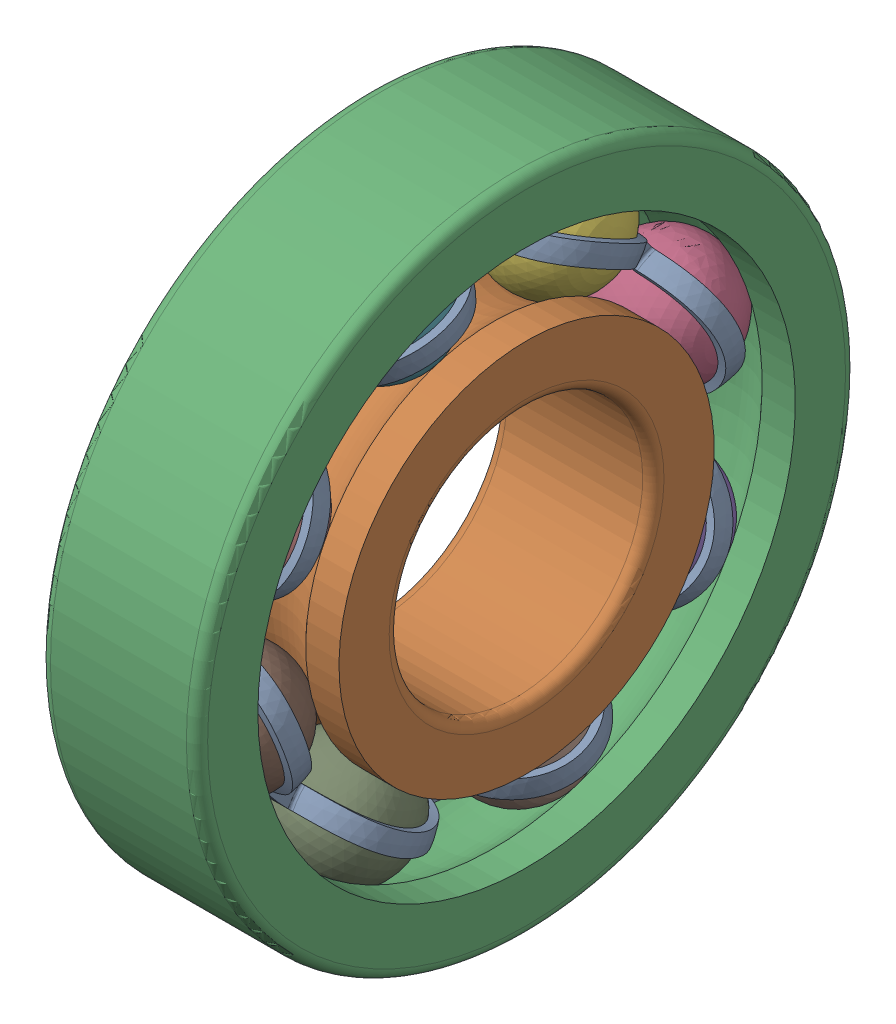
SolidWorks assembly Bearing, configuration Default. Lengths in mm.
Overall size (40.86 130 130).
12 component instances, 4 part files, 19 mates.
Components (placement in the parent):
- Cage-1-1: Cage-1 [Default] at (8 0 0) x (0 0.887512 -0.460785) z (-1 0 0) size (94 94 13.65)
- Inner ring-1-1: Inner ring-1 [Default] x (1 0 0) z (0 -0.968163 -0.250319) size (31 74 74)
- Outer Ring-2-1: Outer Ring-2 [Default] at origin size (31 130 130)
- Ball-1-1: Ball-1 [Default] at (0 13.5784 -42.9025) size (24 24 24)
- Ball-1-2: Ball-1 [Default] at (0 -20.7353 -39.938) x (0.328011 -0.056865 -0.942961) z (0.370605 0.925911 0.073079) size (24 24 24)
- Ball-1-3: Ball-1 [Default] at (0 39.938 -20.7353) size (24 24 24)
- Ball-1-4: Ball-1 [Default] at (0 42.9025 13.5784) size (24 24 24)
- Ball-1-5: Ball-1 [Default] at (0 -42.9025 -13.5784) size (24 24 24)
- Ball-1-6: Ball-1 [Default] at (0 -39.938 20.7353) x (-0.255257 -0.888135 0.382178) z (0.631463 0.146197 0.761499) size (24 24 24)
- Ball-1-7: Ball-1 [Default] at (0 20.7353 39.938) size (24 24 24)
- Ball-1-8: Ball-1 [Default] at (0 -13.5784 42.9025) x (0.464784 0.011441 0.88535) z (-0.713496 -0.587267 0.382155) size (24 24 24)
- Cage-1-3: Cage-1 [Default] at (-8 0 0) x (0 -0.460785 -0.887512) z (1 0 0) size (94 94 13.65)
Mates (geometry in assembly coordinates):
- Coincident1: coordinate: point of Outer Ring-2-1
- Concentric1: concentric: sphere of Cage-1-1; sphere of Ball-1-1
- Concentric2: concentric: sphere of Cage-1-1; sphere of Ball-1-3
- Concentric3: concentric: sphere of Cage-1-1; sphere of Ball-1-4
- Concentric4: concentric: sphere of Cage-1-1; sphere of Ball-1-7
- Concentric5: concentric: sphere of Cage-1-1; sphere of Ball-1-8
- Concentric6: concentric: sphere of Cage-1-1; sphere of Ball-1-6
- Concentric7: concentric: sphere of Cage-1-1; sphere of Ball-1-5
- Concentric8: concentric: sphere of Cage-1-1; sphere of Ball-1-2
- Tangent4: tangent anti-aligned: torus of Outer Ring-2-1; sphere of Ball-1-2
- Tangent5: tangent anti-aligned: torus of Outer Ring-2-1; sphere of Ball-1-1
- Tangent6: tangent anti-aligned: torus of Outer Ring-2-1; sphere of Ball-1-3
- Tangent7: tangent anti-aligned: torus of Outer Ring-2-1; sphere of Ball-1-4
- Tangent8: tangent anti-aligned: torus of Outer Ring-2-1; sphere of Ball-1-7
- Coincident3: coincident anti-aligned: plane of Cage-1-1 through (0 0 0) normal (-1 0 0); plane of Cage-1-3 through (0 0 0) normal (1 0 0)
- Concentric18: concentric anti-aligned: cylinder of Cage-1-1 through (13.5 -44.833 3.8733) axis (-1 0 0) radius 1; cylinder of Cage-1-3 through (-13.5 -44.833 3.8733) axis (1 0 0) radius 1
- Concentric19: concentric anti-aligned: cylinder of Cage-1-1 through (13.5 -34.4406 -28.9629) axis (-1 0 0) radius 1; circle of Cage-1-3
- Concentric20: concentric aligned: cylinder of Inner ring-1-1 through (-62.7041 0 0) axis (-1 0 0) radius 25; cylinder of Outer Ring-2-1 through (-41.5277 0 0) axis (-1 0 0) radius 65
- Tangent9: tangent anti-aligned: torus of Inner ring-1-1; sphere of Ball-1-6
